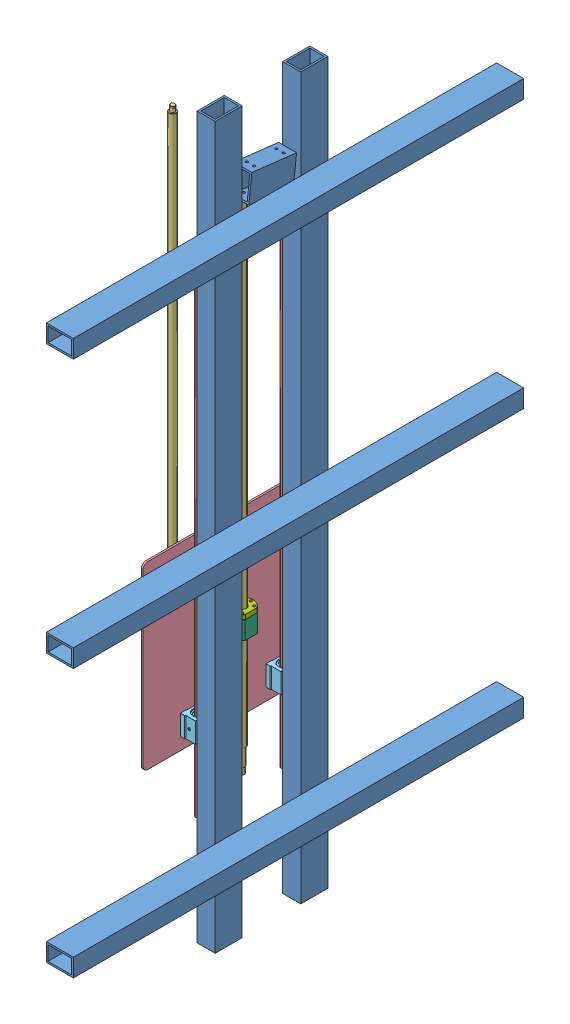
SolidWorks assembly Станина, configuration По умолчанию. Lengths in mm.
Overall size (294.07 1600 1000).
22 component instances, 9 part files, 4 mates.
Components (placement in the parent):
- Основание-1: Основание [По умолчанию] at (125.5226 580.7301 -9.2169) size (294.07 1600 1000)
  - Труба стальная 60х40х4-1: Труба стальная 60х40х4 [1000] at (-49.6739 3.0422 46.6321) size (60 40 1000)
  - Труба стальная 60х40х4-2: Труба стальная 60х40х4 [1600] at (-99.6739 -576.9578 141.6321) x (0 0 1) z (0 -1 0) size (60 40 1600)
  - Труба стальная 60х40х4-3: Труба стальная 60х40х4 [1000] at (-49.6739 -591.9578 46.6321) size (60 40 1000)
  - Труба стальная 60х40х4-4: Труба стальная 60х40х4 [1000] at (-49.6739 -1186.9578 46.6321) size (60 40 1000)
  - Труба стальная 60х40х4-5: Труба стальная 60х40х4 [1600] at (-99.6739 -576.9578 -48.3679) x (0 0 1) z (0 -1 0) size (60 40 1600)
  - SBR16-1: SBR16 [L1100] at (-144.6739 -610.218 141.6321) x (0 1 0) z (0 0 1) size (1100 33 40)
  - Винт ШВП RM1605-1: Винт ШВП RM1605 [L1150] at (-305.7453 -1073.604 40.092) size (16 1150 16)
  - SBR16-2: SBR16 [L1100] at (-144.6739 -610.218 -48.3679) x (0 1 0) z (0 0 1) size (1100 33 40)
- Стол-1: Стол [По умолчанию] at (-94.0018 -252.8588 -15.3136) x (0 0 -1) z (1 0 0) size (400 400 44)
  - Плита стола-1: Плита стола [По умолчанию] at (-52.7289 -0.1217 50.8505) size (400 400 4)
  - SBR16UU-1: SBR16UU [По умолчанию] at (-147.7289 149.8783 74.8505) x (1 0 0) z (0 -1 0) size (45 32 45)
  - SBR16UU-2: SBR16UU [По умолчанию] at (-147.7289 -150.1217 74.8505) x (1 0 0) z (0 -1 0) size (45 32 45)
  - SBR16UU-3: SBR16UU [По умолчанию] at (42.2711 149.8783 74.8505) x (-1 0 0) z (0 1 0) size (45 32 45)
  - SBR16UU-4: SBR16UU [По умолчанию] at (42.2711 -150.1217 74.8505) x (-1 0 0) z (0 1 0) size (45 32 45)
  - bsh16-1: bsh16 [По умолчанию] at (-46.8326 19.8783 87.6733) x (1 0 0) z (0 -1 0) size (52 40 40)
  - RM1605-1: RM1605 [RM1605] at (-52.7289 29.8783 74.8505) x (0 0 -1) z (0 1 0) size (40 48 48.86)
- Винт ШВП RM1605-1: Винт ШВП RM1605 [L1150] at (-19.1513 -545.2669 37.4153) x (0.995913 0 0.090315) z (-0.090315 0 0.995913) size (16 1150 16)
- Стойка опоры продольной оси-1: Стойка опоры продольной оси [По умолчанию] at (46.1706 590.115 61.1237) x (0 -0.993054 0.117658) z (0 -0.117658 -0.993054) size (89.5 93.94 100)
  - Труба стальная 60х40х4-1: Труба стальная 60х40х4 [100 с отверстиями] at (-41.8731 20.3219 21.5545) size (60 40 100)
  - пластина подшипниковой опоры-1: пластина подшипниковой опоры [Увеличенная] at (-7.8731 54.3219 21.5545) x (0 0 1) z (-1 0 0) size (80 71 4)
  - BK12-1: BK12 [Default] at (4.6269 47.3219 21.5545) x (0 0 1) z (-1 0 0) size (60 46.94 35.34)
Mates (geometry in assembly coordinates):
- Концентричный1: concentric anti-aligned: cylinder of Основание-1/SBR16-2 through (-19.1513 520.5121 -57.5847) axis (0 -1 0) radius 8; cylinder of Стол-1/SBR16UU-3 through (-19.1513 -59.6373 -57.5847) axis (0 1 0) radius 8
- Концентричный2: concentric aligned: cylinder of Основание-1/SBR16-1 through (-19.1513 520.5121 132.4153) axis (0 -1 0) radius 8; cylinder of Стол-1/SBR16UU-2 through (-19.1513 -446.3237 132.4153) axis (0 -1 0) radius 8
- Концентричный6: concentric aligned: cylinder of Стол-1/bsh16-1 through (-19.1513 -271.9805 37.4153) axis (0 1 0) radius 14; cylinder of Винт ШВП RM1605-1 through (-19.1513 604.7331 37.4153) axis (0 1 0) radius 8
- Совпадение1: coincident anti-aligned: plane of Основание-1/Труба стальная 60х40х4-1 through (45.8487 563.7723 -462.5847) normal (-1 0 0); plane of Стойка опоры продольной оси-1/Труба стальная 60х40х4-1 through (45.8487 664.8358 80.9151) normal (1 0 0)
